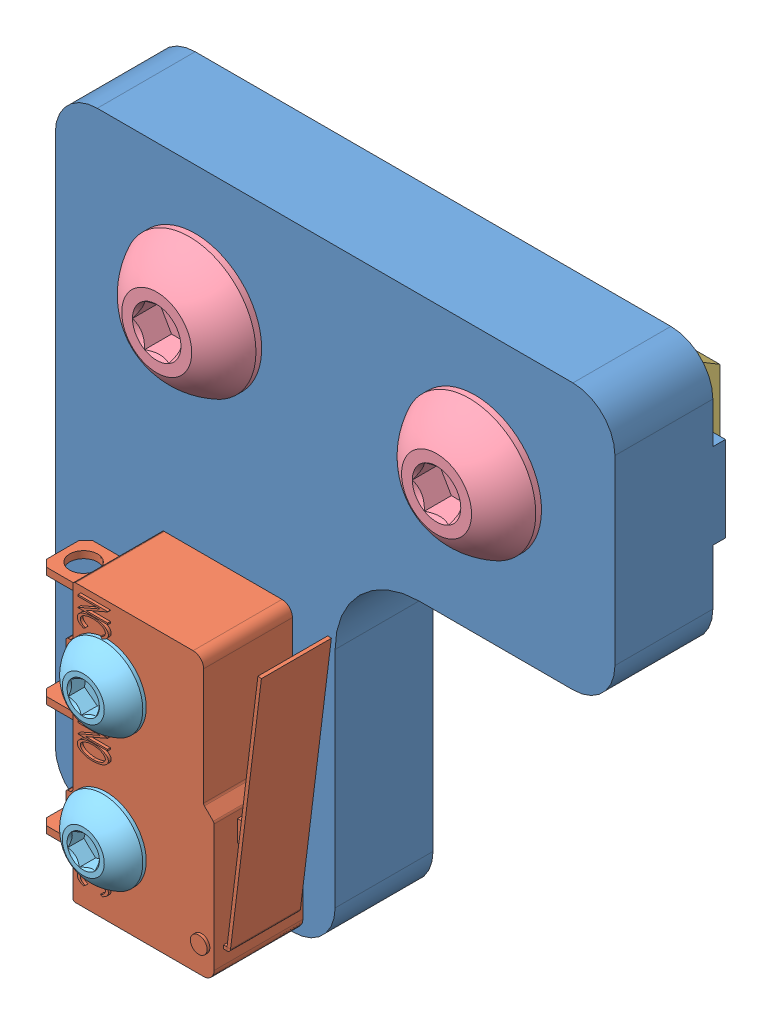
SolidWorks assembly Y_Axis_Endstop, configuration Default. Lengths in mm.
Overall size (40 44 20.62).
8 component instances, 5 part files, 19 mates.
Components (placement in the parent):
- Y Endstop Mount-1: Y Endstop Mount [Default] at origin size (40 44 7.9)
- Micro Switch Button-1: Micro Switch Button [Default] at (12.4 9.4 10.175) x (0 0 1) z (0 1 0) size (6.75 16.71 19.86)
- HNTTSN5-5-1: HNTTSN5-5 [Default] at (10 35 -1.2) x (0 0 1) z (1 0 0) size (4.3 10 10)
- HNTTSN5-5-2: HNTTSN5-5 [Default] at (30 35 -1.2) x (0 0 1) z (-1 0 0) size (4.3 10 10)
- 5mmX12mm_Buttonhead(McMaster_92095A210)-1: 5mmX12mm_Buttonhead(McMaster_92095A210) [92095A210] at (30 35 9.75) x (0.866025 -0.5 0) z (0 0 1) size (9.5 9.5 15.22)
- 5mmX12mm_Buttonhead(McMaster_92095A210)-2: 5mmX12mm_Buttonhead(McMaster_92095A210) [92095A210] at (10 35 9.75) x (0 -1 0) z (0 0 1) size (9.5 9.5 15.22)
- 3mmX12mm_Buttonhead(McMaster_92095A183)-1: 3mmX12mm_Buttonhead(McMaster_92095A183) [92095A183] at (10 5.5 15) x (0.692855 0.721077 0) z (0 0 1) size (5.7 5.7 13.97)
- 3mmX12mm_Buttonhead(McMaster_92095A183)-2: 3mmX12mm_Buttonhead(McMaster_92095A183) [92095A183] at (10 15 15) x (0.383049 -0.923728 0) z (0 0 1) size (5.7 5.7 13.97)
Mates (geometry in assembly coordinates):
- Concentric1: concentric anti-aligned: cylinder of Y Endstop Mount-1 through (10 35 7) axis (0 0 -1) radius 2.5; cylinder of 5mmX12mm_Buttonhead(McMaster_92095A210)-2 through (10 35 9.75) axis (0 0 1) radius 4.75
- Concentric2: concentric anti-aligned: cylinder of Y Endstop Mount-1 through (30 35 7) axis (0 0 -1) radius 2.5; cylinder of 5mmX12mm_Buttonhead(McMaster_92095A210)-1 through (30 35 9.75) axis (0 0 1) radius 4.75
- Coincident1: coincident anti-aligned: plane of Y Endstop Mount-1 through (26 19 7) normal (0 0 1); plane of 5mmX12mm_Buttonhead(McMaster_92095A210)-2 through (5.25 35 7) normal (0 0 -1)
- Coincident2: coincident anti-aligned: plane of Y Endstop Mount-1 through (26 19 7) normal (0 0 1); plane of 5mmX12mm_Buttonhead(McMaster_92095A210)-1 through (27.625 30.8864 7) normal (0 0 -1)
- Concentric3: concentric anti-aligned: cylinder of HNTTSN5-5-2 through (30 35 -1.2) axis (0 0 -1) radius 2.067; cylinder of 5mmX12mm_Buttonhead(McMaster_92095A210)-1 through (30 35 9.75) axis (0 0 1) radius 4.75
- Concentric4: concentric anti-aligned: cylinder of HNTTSN5-5-1 through (10 35 -1.2) axis (0 0 -1) radius 2.067; cylinder of 5mmX12mm_Buttonhead(McMaster_92095A210)-2 through (10 35 9.75) axis (0 0 1) radius 4.75
- Distance1: distance = 2 mm anti-aligned: plane of Y Endstop Mount-1 through (26 19 0) normal (0 0 -1); plane of HNTTSN5-5-1 through (15 32.1 -2) normal (0 0 1)
- Distance2: distance = 2 mm anti-aligned: plane of Y Endstop Mount-1 through (26 19 0) normal (0 0 -1); plane of HNTTSN5-5-2 through (25 30 -2) normal (0 0 1)
- Parallel1: parallel aligned: plane of Y Endstop Mount-1 through (40 28 7) normal (1 0 0); plane of HNTTSN5-5-2 through (35 35 -1.2) normal (1 0 0)
- Parallel2: parallel aligned: plane of Y Endstop Mount-1 through (40 28 7) normal (1 0 0); plane of HNTTSN5-5-1 through (15 35 -1.2) normal (1 0 0)
- Concentric5: concentric anti-aligned: cylinder of Y Endstop Mount-1 through (10 15 7) axis (0 0 -1) radius 1.1; cylinder of Micro Switch Button-1 through (10 15 7) axis (0 0 1) radius 1.35
- Coincident7: coincident anti-aligned: plane of Y Endstop Mount-1 through (26 19 7) normal (0 0 1); plane of Micro Switch Button-1 through (7.8 0.6 7) normal (0 0 -1)
- Parallel3: parallel aligned: plane of Y Endstop Mount-1 through (3 0 7) normal (0 -1 0); plane of Micro Switch Button-1 through (16.95 0.4 13.35) normal (0 -1 0)
- Concentric6: concentric aligned: cylinder of Micro Switch Button-1 through (10 15 7) axis (0 0 1) radius 1.35; cylinder of 3mmX12mm_Buttonhead(McMaster_92095A183)-2 through (10 15 15) axis (0 0 1) radius 2.85
- Concentric7: concentric aligned: cylinder of Micro Switch Button-1 through (10 5.5 7) axis (0 0 1) radius 1.35; cylinder of 3mmX12mm_Buttonhead(McMaster_92095A183)-1 through (10 5.5 15) axis (0 0 1) radius 2.85
- Coincident9: coincident anti-aligned: plane of Micro Switch Button-1 through (7.8 0.6 13.35) normal (0 0 1); plane of 3mmX12mm_Buttonhead(McMaster_92095A183)-2 through (7.3674 13.9083 13.35) normal (0 0 -1)
- Coincident10: coincident anti-aligned: plane of Micro Switch Button-1 through (7.8 0.6 13.35) normal (0 0 1); plane of 3mmX12mm_Buttonhead(McMaster_92095A183)-1 through (12.0551 3.5254 13.35) normal (0 0 -1)
- Parallel4: parallel anti-aligned: plane of Y Endstop Mount-1 through (37 44 7) normal (0 1 0); plane of 5mmX12mm_Buttonhead(McMaster_92095A210)-2 through (10.866 36.5 7.825) normal (0 -1 0)
- Parallel5: parallel anti-aligned: plane of Y Endstop Mount-1 through (37 44 7) normal (0 1 0); plane of 5mmX12mm_Buttonhead(McMaster_92095A210)-1 through (30.866 36.5 7.825) normal (0 -1 0)
